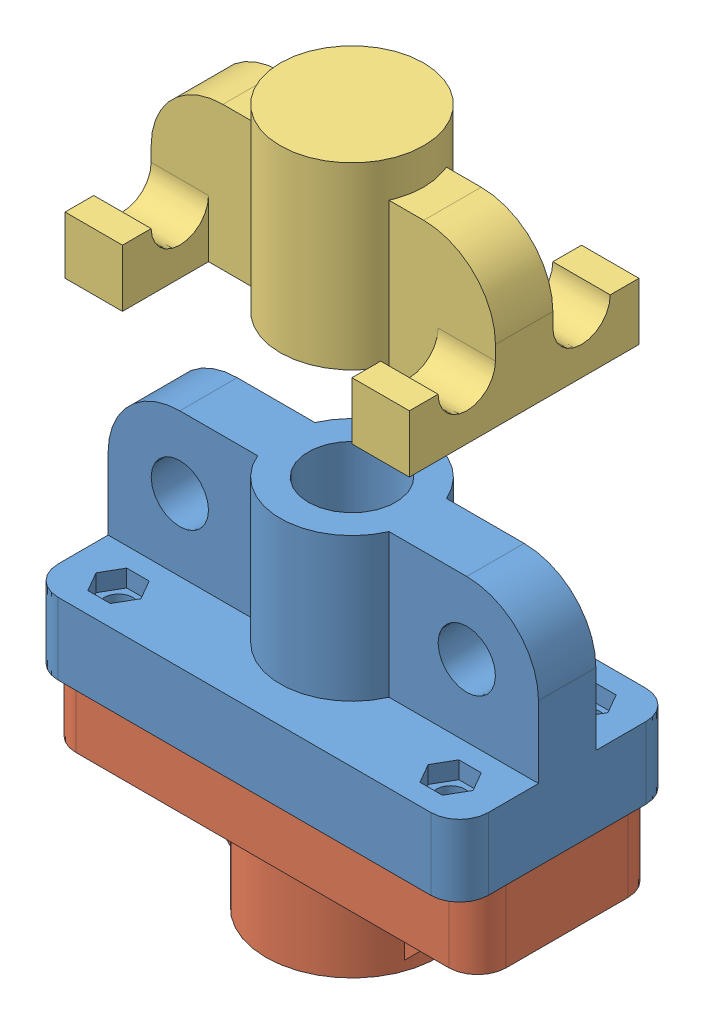
SolidWorks assembly Pen Mount Assembly, configuration Sharpie Config. Lengths in mm.
Overall size (60 97 32).
3 component instances, 3 part files, 7 mates.
Components (placement in the parent):
- Top-1: Top [Sharpie] at origin size (60 30 30)
- Bottom-1: Bottom [Sharpie] at (0 -10 0) x (-1 0 0) z (0 0 -1) size (60 22 25)
- Restraint-1: Restraint [Sharpie] at (0 50 0) x (-1 0 0) z (0 0 -1) size (48 25 32)
Mates (geometry in assembly coordinates):
- Coincident1: coordinate: point of Top-1; point of assembly
- Concentric3: concentric aligned: circle of Bottom-1; circle of Top-1
- Parallel2: parallel aligned: plane of Bottom-1 through (30 0 12.5) normal (0 0 1); plane of Top-1 through (-30 10 15) normal (0 0 1)
- Concentric4: concentric anti-aligned: circle of Top-1; circle of Restraint-1
- Parallel3: parallel aligned: plane of Top-1 through (-52.319 30 4) normal (0 0 1); plane of Restraint-1 through (24 70 4) normal (0 0 1)
- Distance1: distance = 20 mm anti-aligned: plane of Top-1 through (-52.319 30 0) normal (0 1 0); plane of Restraint-1 through (0 50 0) normal (0 -1 0)
- Coincident2: coincident anti-aligned: plane of Top-1 through (-30 0 15) normal (0 -1 0); plane of Bottom-1 through (30 0 -12.5) normal (0 1 0)
